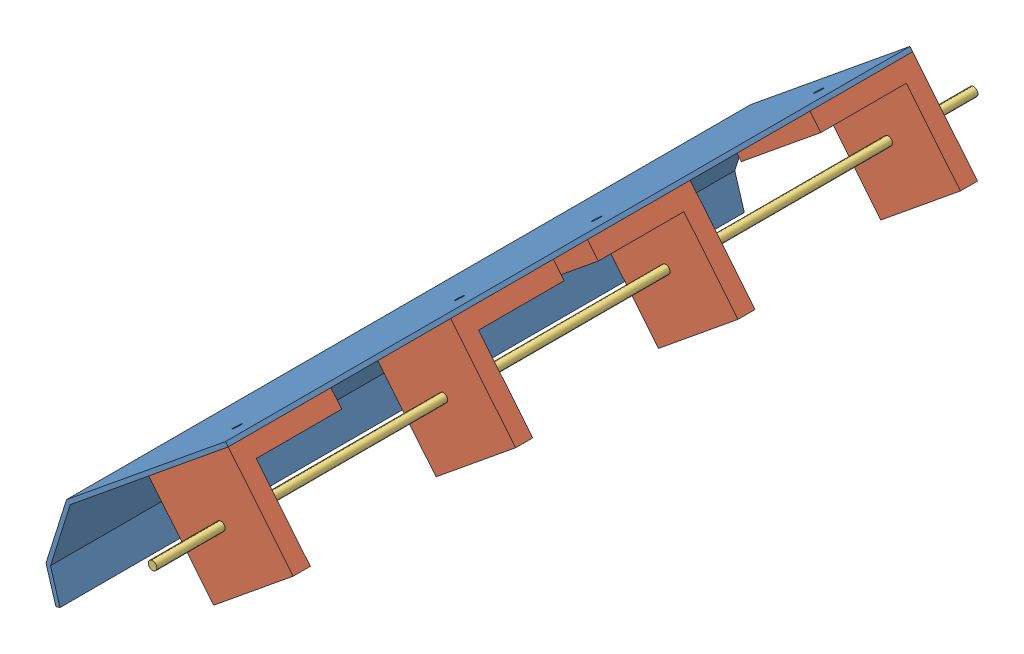
SolidWorks assembly roller assem, configuration Default. Lengths in mm.
Overall size (104.32 85.05 304.8).
6 component instances, 3 part files, 9 mates.
Components (placement in the parent):
- roller1-1: roller1 [Default] at (129.684 231.6799 -186.4831) x (0.632436 -0.774613 0) z (0 0 1) size (26.29 102.27 254)
- roller2-1: roller2 [Default] at (138.543 254.1216 67.5169) x (0.774613 0.632436 0) z (0 0 -1) size (38.1 38.1 38.1)
- roller2-2: roller2 [Default] at (138.543 254.1216 -15.0331) x (0.774613 0.632436 0) z (0 0 -1) size (38.1 38.1 38.1)
- roller2-3: roller2 [Default] at (138.543 254.1216 -103.9331) x (-0.774613 -0.632436 0) z (0 0 1) size (38.1 38.1 38.1)
- roller2-6: roller2 [Default] at (138.543 254.1216 -186.4831) x (-0.774613 -0.632436 0) z (0 0 1) size (38.1 38.1 38.1)
- roller3-1: roller3 [Default] at (138.543 254.1216 -211.8831) size (3.17 3.17 304.8)
Mates (geometry in assembly coordinates):
- 일치1: coincident aligned: circle of roller1-1; circle of roller2-1
- 일치2: coincident aligned: circle of roller1-1; circle of roller2-2
- 일치3: coincident aligned: circle of roller1-1; circle of roller2-3
- 일치4: coincident aligned: circle of roller1-1; circle of roller2-6
- 동심1: concentric anti-aligned: cylinder of roller2-1 through (138.543 254.1216 61.1669) axis (0 0 1) radius 1.5875; cylinder of roller3-1 through (138.543 254.1216 92.9169) axis (0 0 -1) radius 1.5875
- 동심2: concentric anti-aligned: cylinder of roller2-2 through (138.543 254.1216 -21.3831) axis (0 0 1) radius 1.5875; cylinder of roller3-1 through (138.543 254.1216 92.9169) axis (0 0 -1) radius 1.5875
- 동심3: concentric aligned: cylinder of roller2-3 through (138.543 254.1216 -97.5831) axis (0 0 -1) radius 1.5875; cylinder of roller3-1 through (138.543 254.1216 92.9169) axis (0 0 -1) radius 1.5875
- 동심4: concentric aligned: cylinder of roller2-6 through (138.543 254.1216 -180.1331) axis (0 0 -1) radius 1.5875; cylinder of roller3-1 through (138.543 254.1216 92.9169) axis (0 0 -1) radius 1.5875
- 너비1: width anti-aligned: plane of roller3-1 through (138.543 254.1216 -211.8831) normal (0 0 -1); plane of roller2-1 through (138.543 254.1216 92.9169) normal (0 0 1); plane of roller3-1 through (138.543 254.1216 67.5169) normal (0 0 1); plane of roller2-6 through (138.543 254.1216 -186.4831) normal (0 0 -1)
